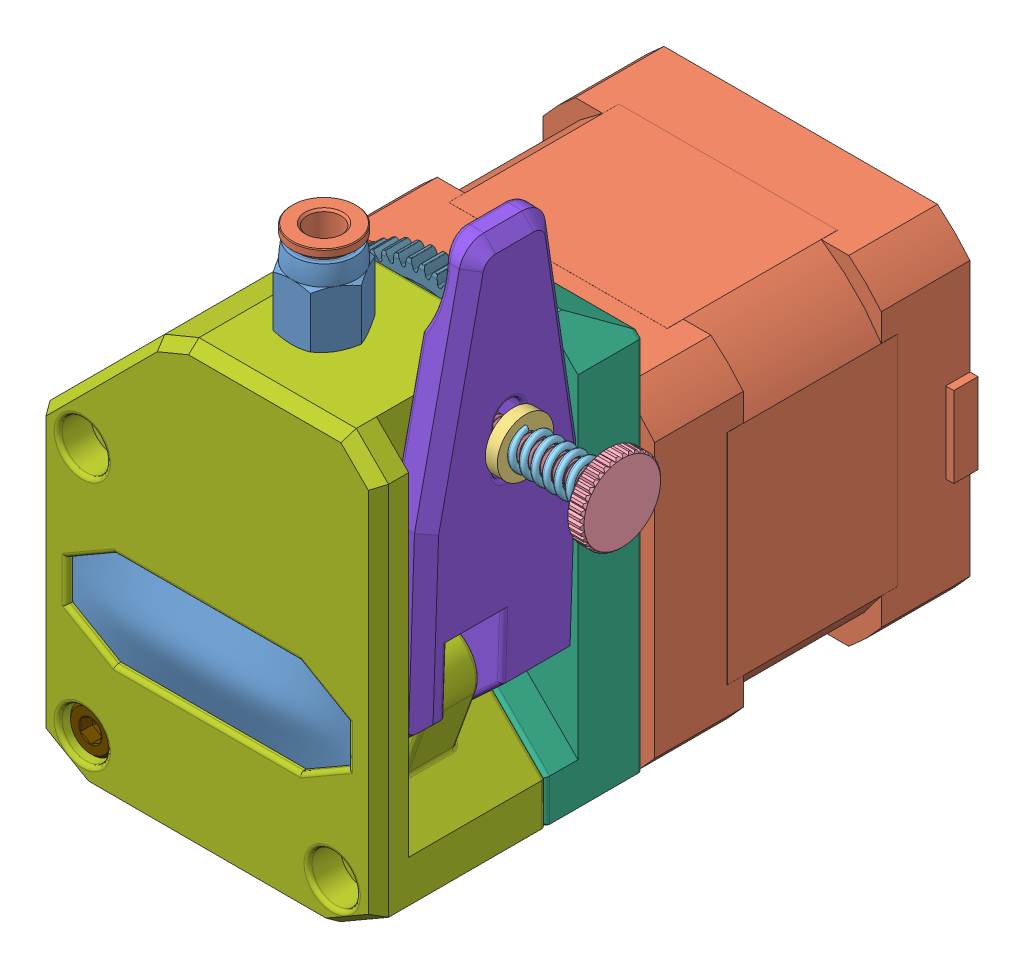
SolidWorks assembly BMG Extruder, configuration Default. Lengths in mm.
Overall size (58.01 72.87 75.12).
27 component instances, 20 part files, 3 mates.
Components (placement in the parent):
- BMG Extruder.step-1: BMG Extruder.step [Default] at origin size (58 72.86 40.49)
  - PC4-M6C complete.step-1: PC4-M6C complete.step [Default] at origin size (9.24 15.06 8)
    - body.step-1: body.step [Default] at (25 54 -10.5) size (9.24 13.33 8)
    - release sleeve.step-1: release sleeve.step [Default] at (25 54 -10.5) size (8 6.5 8)
  - thumbscrew assembly.step-1: thumbscrew assembly.step [Default] at origin size (22.05 9.99 9.99)
    - M3 washer - nylon.step-1: M3 washer - nylon.step [Default] at (46.0002 49.5 -14.5) x (0 0.555211 -0.83171) z (-1 0 0) size (7 7 1.5)
    - Thumbscrew.step-1: Thumbscrew.step [Default] at (56 49.5 -14.5) x (0 1 0) z (0 0 -1) size (9.99 22.05 9.99)
    - spring.step-1: spring.step [Default] at (56 49.5 -14.5) x (0 1 0) z (0 0 1) size (5 10.9 5.01)
  - BMG Back.step-1: BMG Back.step [Default] at (0 0 -33) size (42 54 22.4)
  - BMG Front.step-1: BMG Front.step [Default] x (-1 0 0) z (0 0 -1) size (42 54 21.01)
  - BMG Arm.step-1: BMG Arm.step [Default] at (42.8457 17.2686 -24.5) x (0 0 1) z (-0.999441 0.033421 0) size (20.01 55.04 17.5)
  - M3x30 shaft.step-1: M3x30 shaft.step [Default] at (36 22 -16.3) size (3 3 30)
  - M3x20 shaft.step-1: M3x20 shaft.step [Default] at (29.5219 37.7253 -14.5) x (0.999441 -0.033421 0) z (0 0 1) size (3 3 20)
  - 3x5x7 needle bearing.step-1: 3x5x7 needle bearing.step [Default] at (29.5219 37.7253 -11) x (1 -0.00091 0) z (0 0 1) size (5 5 7)
  - 3x5x7 needle bearing.step-2: 3x5x7 needle bearing.step [Default] at (29.5219 37.7253 -18) x (1 -0.00091 0) z (0 0 1) size (5 5 7)
  - BMG filament gear - driven.step-1: BMG filament gear - driven.step [Default] at (21.0238 37.5488 -21.5) x (0.999784 0.020767 0) z (0.020767 -0.999784 0) size (9.5 14.01 9.51)
  - 5x8x2.5 MR58(zz) ball bearing.step-1: 5x8x2.5 MR58(zz) ball bearing.step [Default] at (21 37.7 -5.25) x (0 0 1) z (-1 0 0) size (2.5 8 8)
  - 5x8x2.5 MR58(zz) ball bearing.step-2: 5x8x2.5 MR58(zz) ball bearing.step [Default] at (21 37.7 -31.15) x (0 0 1) z (-1 0 0) size (2.5 8 8)
  - BMG shaft.step-1: BMG shaft.step [Default] at (21 37.7 -29.4) x (0.999875 -0.015798 0) z (-0.015798 -0.999875 0) size (25.97 28.25 26)
  - BMG filament gear - driver.step-1: BMG filament gear - driver.step [Default] at (12.5011 37.8343 -21.5) x (0.999875 -0.015798 0) z (-0.015798 -0.999875 0) size (9.5 14.01 9.51)
  - BMG motor gear.step-1: BMG motor gear.step [Default] at (21.0565 21.0565 -34.5) x (-0.13775 -0.990467 0) z (-0.990467 0.13775 0) size (9.95 13 10.56)
  - M3x8x5 threaded insert.step-1: M3x8x5 threaded insert.step [Default] at (34 49.5 -14.5) x (0 -1 0) z (0 0 1) size (4.99 8.1 4.99)
  - M3x35 cap head screw (partial thread).step-1: M3x35 cap head screw (partial thread).step [Default] at (5.5 5.5 -4) x (1 0 0) z (0 -1 0) size (5.5 38 5.5) (hidden)
  - M3x35 cap head screw (partial thread).step-2: M3x35 cap head screw (partial thread).step [Default] at (5.5 36.5 -4) x (1 0 0) z (0 -1 0) size (5.5 38 5.5) (hidden)
  - M3x35 cap head screw (partial thread).step-3: M3x35 cap head screw (partial thread).step [Default] at (36.5 5.5 -4) x (1 0 0) z (0 -1 0) size (5.5 38 5.5) (hidden)
  - Decal.step-1: Decal.step [Default] at (19.6812 14.9904 -0.6) size (37.89 14.89 3.73)
- STEPPER-1: STEPPER [Default] at (21 21 -73.6349) x (0 -1 0) z (0 0 1) size (42.02 53.01 63.12)
Mates (geometry in assembly coordinates):
- Concentric1: concentric aligned: cylinder of BMG Extruder.step-1/BMG Back.step-1 through (21 21 -33) axis (0 0 1) radius 11.1; cylinder of STEPPER-1 through (21 21 -33) axis (0 0 1) radius 11
- Concentric2: concentric aligned: cylinder of BMG Extruder.step-1/BMG Back.step-1 through (5.5 5.5 -33) axis (0 0 1) radius 1.6; cylinder of STEPPER-1 through (5.5 5.5 -38) axis (0 0 1) radius 1.2295
- Distance1: distance = 1.5189 mm anti-aligned: plane of BMG Extruder.step-1/BMG Back.step-1 through (21 27 -33) normal (0 0 -1); plane of STEPPER-1 through (21 21 -34.5189) normal (0 0 1)
